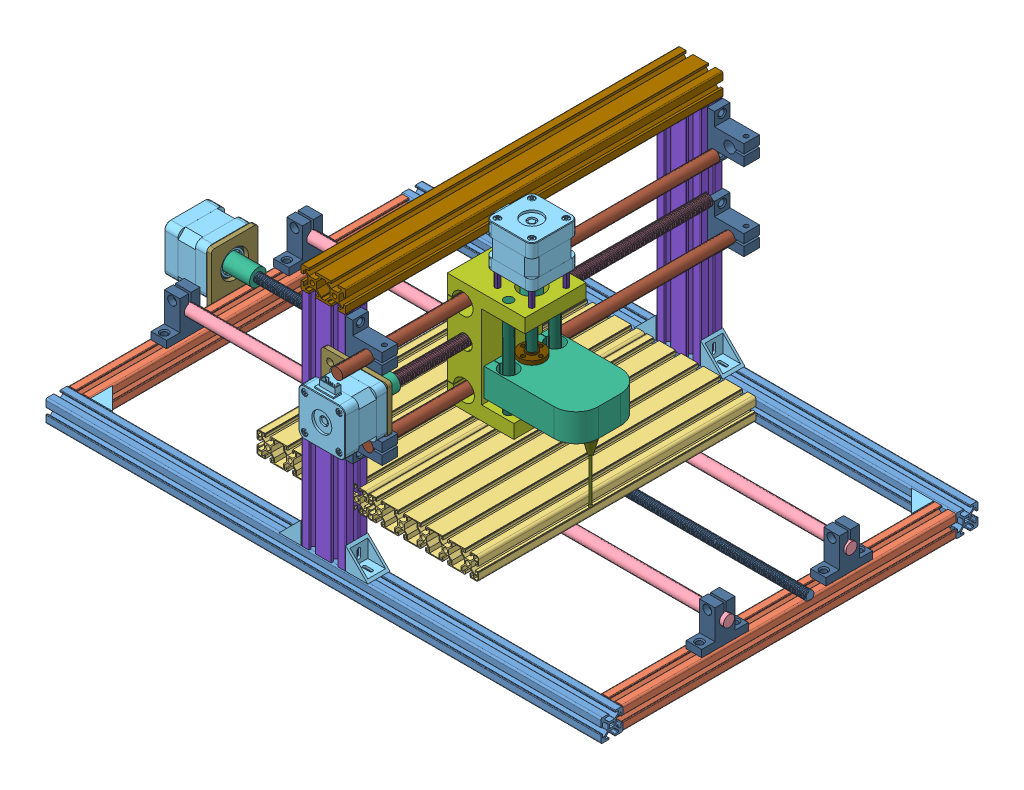
SolidWorks assembly CMM_v2, configuration Default. Lengths in mm.
Overall size (560.56 265.37 382.4).
67 component instances, 25 part files, 156 mates.
Components (placement in the parent):
- ALU 500-2: ALU 500 [Default] at (-29.4139 -47.6481 461.8459) x (0 0 -1) z (1 0 0) size (20 20 500)
- ALU 500-3: ALU 500 [Default] at (-29.4139 -47.6481 141.8459) x (0 0 -1) z (1 0 0) size (20 20 500)
- ALU 300-2: ALU 300 [Default] at (-19.4139 -47.6481 151.8459) size (20 20 300)
- ALU 300-3: ALU 300 [Default] at (460.5861 -47.6481 151.8459) size (20 20 300)
- ban_nhom-1: ban_nhom [Default] at (158.2326 11.3519 209.5255) size (100 20 250)
- ban_nhom-2: ban_nhom [Default] at (258.2326 11.3519 209.5255) size (100 20 250)
- truc_10-1: truc_10 [Default] at (-29.4139 -17.6481 245.8459) x (0 -1 0) z (0 0 1) size (10 500 10)
- truc_10-2: truc_10 [Default] at (-27.7739 -17.6481 357.8459) x (0 -1 0) z (0 0 1) size (10 500 10)
- nema 17-4: nema 17 [Default] at (-33.4139 -17.6481 301.8459) x (0 0 -1) z (1 0 0) size (42 48.2 62.55)
- khop_noi_truc-1: khop_noi_truc [Default] at (-8.4139 -17.6481 301.8459) x (0 0.838957 0.544198) z (0 -0.544198 0.838957) size (15 25 15)
- lmu10-1: lmu10 [Default] at (277.237 -17.6481 245.8459) x (0 1 0) z (0 0 1) size (16 32 16)
- lmu10-2: lmu10 [Default] at (307.4891 -17.6481 357.8459) x (0 1 0) z (0 0 1) size (16 32 16)
- Aluminum Profile 2040-1: Aluminum Profile 2040 [Default] at (220.5861 162.3519 141.8459) x (0 0 -1) z (0 1 0) size (20 40 200)
- Aluminum Profile 2040-2: Aluminum Profile 2040 [Default] at (220.5861 162.3519 461.8459) x (0 0 -1) z (0 1 0) size (20 40 200)
- Aluminum Profile 2040 300mm-1: Aluminum Profile 2040 300mm [Default] at (220.5861 172.3519 471.8459) x (0 -1 0) z (0 0 1) size (20 40 340)
- SK10-1: SK10 [Default] at (240.5861 49.3219 471.8459) x (0 0 -1) z (0 -1 0) size (14 33 42)
- SK10-2: SK10 [Default] at (240.5861 49.3219 145.8459) x (0 0 -1) z (0 -1 0) size (14 33 42)
- SK10-3: SK10 [Default] at (240.5861 119.5072 145.8459) x (0 0 -1) z (0 -1 0) size (14 33 42)
- SK10-5: SK10 [Default] at (240.5861 119.5072 471.8459) x (0 0 -1) z (0 -1 0) size (14 33 42)
- truc_10_340mm-1: truc_10_340mm [Default] at (260.5861 140.5072 499.541) x (0.996943 -0.078134 0) z (0.078134 0.996943 0) size (10 340 10)
- truc_10_340mm-2: truc_10_340mm [Default] at (260.5861 70.3219 471.8459) x (0.996923 -0.07839 0) z (0.07839 0.996923 0) size (10 340 10)
- ga_dong_co-1: ga_dong_co [Default] at (252.5861 110.2153 475.8459) x (1 0 0) z (0 1 0) size (60 4 42)
- nema 17-5: nema 17 [Default] at (261.5861 110.2153 475.8459) x (1 0 0) z (0 0 -1) size (42 48.2 62.55)
- khop_noi_truc-2: khop_noi_truc [Default] at (261.5861 110.2153 450.8459) x (0.544198 0.838957 0) z (0.838957 -0.544198 0) size (15 25 15)
- Vitme M10 step2mm profile by Taitran Technic-5: Vitme M10 step2mm profile by Taitran Technic [Default] at (261.5861 110.2153 165.8459) x (-0.97024 -0.242147 0) z (-0.242147 0.97024 0) size (10.57 95.57 10.57)
- Vitme M10 step2mm profile by Taitran Technic-6: Vitme M10 step2mm profile by Taitran Technic [Default] at (261.5861 110.2153 260.8459) x (-0.97024 -0.242147 0) z (-0.242147 0.97024 0) size (10.57 95.57 10.57)
- Vitme M10 step2mm profile by Taitran Technic-7: Vitme M10 step2mm profile by Taitran Technic [Default] at (261.5861 110.2153 450.8459) x (0.146687 -0.989183 0) z (0.989183 0.146687 0) size (10.57 95.57 10.57)
- Leadscrew nut M10 step2mm by Taitran Technic-2: Leadscrew nut M10 step2mm by Taitran Technic [Default] at (261.5861 110.2153 330.15) x (-0.214668 -0.976687 0) z (0.976687 -0.214668 0) size (32 19 32)
- nema 17-6: nema 17 [Default] at (294.2592 169.3219 357.65) x (0 0 -1) z (0 -1 0) size (42 48.2 62.55)
- truc_8-1: truc_8 [Default] at (294.2592 54.3219 336.75) size (8 100 8)
- truc_8-2: truc_8 [Default] at (294.2592 54.3219 378.55) size (8 100 8)
- Stylus with thread, M3 XXT Ø 1,50 626113-0151-030-1: Stylus with thread, M3 XXT Ø 1,50 626113-0151-030 [Default] at (354.4778 73.7923 364.8995) x (1 0 0) z (0 -1 0) size (10 10 66)
- khop_noi_truc-3: khop_noi_truc [Default] at (294.2592 144.3219 357.65) x (0.28811 0 -0.957597) z (0.957597 0 0.28811) size (15 25 15)
- coc_dong-1: coc_dong [Default] at (309.7592 154.3219 373.15) size (4.52 23 4.69)
- coc_dong-2: coc_dong [Default] at (309.7592 154.3219 342.15) size (4.52 23 4.69)
- coc_dong-3: coc_dong [Default] at (278.7592 152.2216 373.15) size (4.52 23 4.69)
- coc_dong-4: coc_dong [Default] at (278.7592 154.3219 342.15) size (4.52 23 4.69)
- truc_8-3: truc_8 [Default] at (294.2592 49.7177 357.65) x (0.933443 0 -0.358725) z (0.358725 0 0.933443) size (8 100 8)
- leadscrew m8-1: leadscrew m8 [Default] at (294.2592 100.6553 357.65) size (22 15.03 22)
- ga_dong_co-2: ga_dong_co [Default] at (-33.4139 -26.6481 301.8459) x (0 1 0) z (0 0 -1) size (60 4 42)
- SK10-6: SK10 [Default] at (454.5861 -37.6481 378.8459) size (14 33 42)
- SK10-7: SK10 [Default] at (454.5861 -37.6481 266.8459) size (14 33 42)
- SK10-8: SK10 [Default] at (-29.4139 -37.6481 266.8459) size (14 33 42)
- SK10-9: SK10 [Default] at (-27.7739 -37.6481 378.8459) size (14 33 42)
- Vitme M8 step2mm profile by Taitran Technic-1: Vitme M8 step2mm profile by Taitran Technic [Default] at (-9.2639 -17.6481 301.8459) x (0 -1 0) z (0 0 1) size (8.43 83.01 8.22)
- Vitme M8 step2mm profile by Taitran Technic-2: Vitme M8 step2mm profile by Taitran Technic [Default] at (156.7361 -17.6481 301.8459) x (0 -1 0) z (0 0 1) size (8.43 83.01 8.22)
- Vitme M8 step2mm profile by Taitran Technic-3: Vitme M8 step2mm profile by Taitran Technic [Default] at (239.7361 -17.6481 301.8459) x (0 -1 0) z (0 0 1) size (8.43 83.01 8.22)
- Vitme M8 step2mm profile by Taitran Technic-4: Vitme M8 step2mm profile by Taitran Technic [Default] at (73.7361 -17.6481 301.8459) x (0 -1 0) z (0 0 1) size (8.43 83.01 8.22)
- Vitme M8 step2mm profile by Taitran Technic-5: Vitme M8 step2mm profile by Taitran Technic [Default] at (322.7361 -17.6481 301.8459) x (0 -1 0) z (0 0 1) size (8.43 83.01 8.22)
- Vitme M8 step2mm profile by Taitran Technic-6: Vitme M8 step2mm profile by Taitran Technic [Default] at (405.7361 -17.6481 301.8459) x (0 -1 0) z (0 0 1) size (8.43 83.01 8.22)
- goi_do_dai - Copy-1: goi_do_dai - Copy [Default] at (158.6614 -13.6481 301.8459) x (0 0 1) z (0 1 0) size (57.67 30 30)
- goi_do_dai-1: goi_do_dai [Default] at (247.237 -13.6481 245.8459) x (0 0 1) z (0 1 0) size (57.67 30 31)
- goi_do_dai-2: goi_do_dai [Default] at (277.4891 -13.6481 357.8459) x (0 0 1) z (0 1 0) size (57.67 30 31)
- goi_do_dai-3: goi_do_dai [Default] at (137.237 -13.6481 245.8459) x (0 0 1) z (0 1 0) size (57.67 30 31)
- goi_do_dai-4: goi_do_dai [Default] at (167.4891 -13.6481 357.8459) x (0 0 1) z (0 1 0) size (57.67 30 31)
- Leadscrew nut M8 step2mm by Taitran Technic1-1: Leadscrew nut M8 step2mm by Taitran Technic1 [Default] at (188.6614 -17.6481 301.8459) x (0 1 0) z (0 0 -1) size (22 15.03 22)
- profile angle 20x20-1: profile angle 20x20 [Default] at (250.5861 -27.6481 451.8459) size (20 20 20)
- profile angle 20x20-2: profile angle 20x20 [Default] at (440.5861 -37.6481 161.8459) x (0 0 1) z (0 -1 0) size (20 20 20)
- profile angle 20x20-3: profile angle 20x20 [Default] at (0.5861 -57.6481 441.8459) x (1 0 0) z (0 1 0) size (20 20 20)
- profile angle 20x20-4: profile angle 20x20 [Default] at (0.5861 -57.6481 161.8459) x (0 0 1) z (0 1 0) size (20 20 20)
- profile angle 20x20-6: profile angle 20x20 [Default] at (190.5861 -27.6481 471.8459) x (-1 0 0) z (0 0 -1) size (20 20 20)
- profile angle 20x20-7: profile angle 20x20 [Default] at (190.5861 -27.6481 131.8459) x (0 1 0) z (0 0 1) size (20 20 20)
- profile angle 20x20-8: profile angle 20x20 [Default] at (250.5861 -27.6481 131.8459) size (20 20 20)
- profile angle 20x20-9: profile angle 20x20 [Default] at (200.5861 152.3519 161.8459) x (0 0 1) z (1 0 0) size (20 20 20)
- profile angle 20x20-10: profile angle 20x20 [Default] at (200.5861 152.3519 441.8459) x (0 -1 0) z (1 0 0) size (20 20 20)
- DC_motor_holder_1-1: DC_motor_holder_1 [Default] at (324.2241 75.6553 357.65) x (0 0 1) z (-1 0 0) size (60 25 83)
- ga_1-1: ga_1 [Default] at (280.5861 104.3219 385.15) x (0 1 0) z (-1 0 0) size (100 55 70)
Mates (geometry in assembly coordinates):
- Coincident23: coincident anti-aligned: plane of ALU 500-3 through (470.5861 -47.6481 151.8459) normal (0 0 1); plane of ALU 300-2 through (-19.4139 -47.6481 151.8459) normal (0 0 -1)
- Coincident78: coincident anti-aligned: plane of ban_nhom-1 through (248.2326 13.9019 209.5255) normal (1 0 0); plane of ban_nhom-2 through (248.2326 8.8019 209.5255) normal (-1 0 0)
- Coincident79: coincident aligned: plane of ban_nhom-1 through (245.9826 21.3519 209.5255) normal (0 1 0); plane of ban_nhom-2 through (255.6826 21.3519 209.5255) normal (0 1 0)
- Coincident80: coincident aligned: plane of ban_nhom-1 through (158.2326 11.3519 459.5255) normal (0 0 1); plane of ban_nhom-2 through (258.2326 11.3519 459.5255) normal (0 0 1)
- Concentric7: concentric anti-aligned: cylinder of nema 17-4 through (-9.2639 -17.6481 301.8459) axis (-1 0 0) radius 2.5; cylinder of khop_noi_truc-1 through (-33.4139 -17.6481 301.8459) axis (1 0 0) radius 4
- Coincident117: coincident anti-aligned: plane of nema 17-4 through (-33.4139 -17.6481 301.8459) normal (1 0 0); plane of khop_noi_truc-1 through (-33.4139 -17.6481 301.8459) normal (-1 0 0)
- Concentric16: concentric anti-aligned: cylinder of truc_10-1 through (470.5861 -17.6481 245.8459) axis (-1 0 0) radius 5; cylinder of lmu10-1 through (245.237 -17.6481 245.8459) axis (1 0 0) radius 8
- Concentric17: concentric anti-aligned: cylinder of truc_10-2 through (472.2261 -17.6481 357.8459) axis (-1 0 0) radius 5; cylinder of lmu10-2 through (275.4891 -17.6481 357.8459) axis (1 0 0) radius 8
- Coincident140: coincident aligned: plane of ban_nhom-1 through (198.2326 11.3519 209.5255) normal (0 0 -1); plane of ban_nhom-2 through (298.2326 11.3519 209.5255) normal (0 0 -1)
- Coincident142: coincident anti-aligned: plane of ALU 500-3 through (470.5861 -37.6481 141.8459) normal (0 1 0); plane of Aluminum Profile 2040-1 through (239.5861 -37.6481 132.8459) normal (0 -1 0)
- Coincident143: coincident aligned: plane of ALU 500-3 through (470.5861 -47.6481 131.8459) normal (0 0 -1); plane of Aluminum Profile 2040-1 through (207.5861 -37.6481 131.8459) normal (0 0 -1)
- Distance9: distance = 230 mm aligned: plane of Aluminum Profile 2040-1 through (200.5861 -37.6481 132.8459) normal (-1 0 0); plane of ALU 500-3 through (-29.4139 -47.6481 141.8459) normal (-1 0 0)
- Coincident145: coincident anti-aligned: plane of ALU 500-2 through (470.5861 -37.6481 461.8459) normal (0 1 0); plane of Aluminum Profile 2040-2 through (239.5861 -37.6481 452.8459) normal (0 -1 0)
- Coincident146: coincident aligned: plane of ALU 500-2 through (470.5861 -47.6481 471.8459) normal (0 0 1); plane of Aluminum Profile 2040-2 through (213.5861 -37.6481 471.8459) normal (0 0 1)
- Coincident147: coincident anti-aligned: plane of ALU 500-2 through (470.5861 -47.6481 451.8459) normal (0 0 -1); plane of ALU 300-2 through (-19.4139 -47.6481 451.8459) normal (0 0 1)
- Coincident148: coincident: line of ALU 500-2; line of ALU 300-2 through (-29.4139 -44.5162 451.8459) axis (0 0 -1)
- Coincident149: coincident aligned: plane of Aluminum Profile 2040-1 through (200.5861 -37.6481 144.8459) normal (-1 0 0); plane of Aluminum Profile 2040-2 through (200.5861 -37.6481 452.8459) normal (-1 0 0)
- Coincident150: coincident anti-aligned: plane of Aluminum Profile 2040-2 through (239.5861 162.3519 452.8459) normal (0 1 0); plane of Aluminum Profile 2040 300mm-1 through (213.5861 162.3519 131.8459) normal (0 -1 0)
- Coincident151: coincident aligned: plane of Aluminum Profile 2040-2 through (240.5861 -37.6481 458.8459) normal (1 0 0); plane of Aluminum Profile 2040 300mm-1 through (240.5861 175.3519 131.8459) normal (1 0 0)
- Coincident152: coincident aligned: plane of Aluminum Profile 2040-2 through (213.5861 -37.6481 471.8459) normal (0 0 1); plane of Aluminum Profile 2040 300mm-1 through (201.5861 163.3519 471.8459) normal (0 0 1)
- Coincident153: coincident anti-aligned: plane of Aluminum Profile 2040-2 through (240.5861 -37.6481 458.8459) normal (1 0 0); plane of SK10-1 through (240.5861 49.3219 471.8459) normal (-1 0 0)
- Coincident154: coincident aligned: plane of Aluminum Profile 2040-2 through (233.5861 -37.6481 471.8459) normal (0 0 1); plane of SK10-1 through (257.0861 70.3219 471.8459) normal (0 0 1)
- Coincident155: coincident anti-aligned: plane of Aluminum Profile 2040-2 through (240.5861 -37.6481 458.8459) normal (1 0 0); plane of SK10-5 through (240.5861 119.5072 471.8459) normal (-1 0 0)
- Coincident156: coincident aligned: plane of Aluminum Profile 2040-2 through (233.5861 -37.6481 471.8459) normal (0 0 1); plane of SK10-5 through (257.0861 140.5072 471.8459) normal (0 0 1)
- Coincident157: coincident anti-aligned: plane of Aluminum Profile 2040-1 through (240.5861 -37.6481 138.8459) normal (1 0 0); plane of SK10-2 through (240.5861 49.3219 145.8459) normal (-1 0 0)
- Coincident158: coincident aligned: plane of Aluminum Profile 2040-1 through (239.5861 -37.6481 131.8459) normal (0 0 -1); plane of SK10-2 through (257.0861 70.3219 131.8459) normal (0 0 -1)
- Coincident159: coincident aligned: plane of Aluminum Profile 2040-1 through (239.5861 -37.6481 131.8459) normal (0 0 -1); plane of SK10-3 through (257.0861 140.5072 131.8459) normal (0 0 -1)
- Coincident160: coincident anti-aligned: plane of Aluminum Profile 2040-1 through (240.5861 -37.6481 138.8459) normal (1 0 0); plane of SK10-3 through (240.5861 119.5072 145.8459) normal (-1 0 0)
- Concentric19: concentric aligned: cylinder of SK10-3 through (260.5861 140.5072 145.8459) axis (0 0 -1) radius 5; cylinder of SK10-5 through (260.5861 140.5072 471.8459) axis (0 0 -1) radius 5
- Concentric20: concentric aligned: cylinder of SK10-1 through (260.5861 70.3219 471.8459) axis (0 0 -1) radius 5; cylinder of SK10-2 through (260.5861 70.3219 145.8459) axis (0 0 -1) radius 5
- Concentric22: concentric anti-aligned: cylinder of SK10-5 through (260.5861 140.5072 471.8459) axis (0 0 -1) radius 5; cylinder of truc_10_340mm-1 through (260.5861 140.5072 159.541) axis (0 0 1) radius 5
- Concentric23: concentric anti-aligned: cylinder of SK10-1 through (260.5861 70.3219 471.8459) axis (0 0 -1) radius 5; cylinder of truc_10_340mm-2 through (260.5861 70.3219 131.8459) axis (0 0 1) radius 5
- Coincident162: coincident: point of SK10-1; plane of truc_10_340mm-2 through (260.5861 70.3219 471.8459) normal (0 0 1)
- Coincident163: coincident anti-aligned: plane of Aluminum Profile 2040-2 through (213.5861 -37.6481 471.8459) normal (0 0 1); plane of ga_dong_co-1 through (252.5861 110.2153 471.8459) normal (0 0 -1)
- Distance11: distance = 18 mm anti-aligned: plane of Aluminum Profile 2040-2 through (240.5861 -37.6481 470.8459) normal (1 0 0); plane of ga_dong_co-1 through (222.5861 89.2153 471.8459) normal (-1 0 0)
- Concentric24: concentric aligned: cylinder of ga_dong_co-1 through (261.5861 110.2153 471.8459) axis (0 0 1) radius 12.5; cylinder of nema 17-5 through (261.5861 110.2153 451.6959) axis (0 0 1) radius 2.5
- Coincident167: coincident anti-aligned: plane of ga_dong_co-1 through (252.5861 110.2153 475.8459) normal (0 0 1); plane of nema 17-5 through (261.5861 110.2153 475.8459) normal (0 0 -1)
- Coincident168: coincident aligned: plane of ga_dong_co-1 through (222.5861 131.2153 471.8459) normal (0 1 0); plane of nema 17-5 through (261.5861 131.2153 514.2459) normal (0 1 0)
- Concentric25: concentric anti-aligned: cylinder of nema 17-5 through (261.5861 110.2153 451.6959) axis (0 0 1) radius 2.5; cylinder of khop_noi_truc-2 through (261.5861 110.2153 475.8459) axis (0 0 -1) radius 4
- Coincident169: coincident anti-aligned: plane of nema 17-5 through (261.5861 110.2153 475.8459) normal (0 0 -1); plane of khop_noi_truc-2 through (261.5861 110.2153 475.8459) normal (0 0 1)
- Coincident170: coincident anti-aligned: plane of Vitme M10 step2mm profile by Taitran Technic-5 through (261.5861 110.2153 260.8459) normal (0 0 1); plane of Vitme M10 step2mm profile by Taitran Technic-6 through (261.5861 110.2153 260.8459) normal (0 0 -1)
- Concentric26: concentric aligned: cylinder of Vitme M10 step2mm profile by Taitran Technic-5 through (261.5861 110.2153 265.8459) axis (0 0 -1) radius 4; cylinder of Vitme M10 step2mm profile by Taitran Technic-6 through (261.5861 110.2153 360.8459) axis (0 0 -1) radius 4
- Coincident171: coincident anti-aligned: plane of Vitme M10 step2mm profile by Taitran Technic-6 through (261.5861 110.2153 355.8459) normal (0 0 1); plane of Vitme M10 step2mm profile by Taitran Technic-7 through (261.5861 110.2153 355.8459) normal (0 0 -1)
- Concentric27: concentric anti-aligned: cylinder of Vitme M10 step2mm profile by Taitran Technic-6 through (261.5861 110.2153 360.8459) axis (0 0 -1) radius 4; cylinder of Vitme M10 step2mm profile by Taitran Technic-7 through (261.5861 110.2153 350.8459) axis (0 0 1) radius 4
- Concentric28: concentric anti-aligned: cylinder of khop_noi_truc-2 through (261.5861 110.2153 475.8459) axis (0 0 -1) radius 7.5; cylinder of Vitme M10 step2mm profile by Taitran Technic-7 through (261.5861 110.2153 350.8459) axis (0 0 1) radius 4
- Coincident172: coincident anti-aligned: plane of khop_noi_truc-2 through (261.5861 110.2153 450.8459) normal (0 0 -1); plane of Vitme M10 step2mm profile by Taitran Technic-7 through (261.5861 110.2153 450.8459) normal (0 0 1)
- Concentric29: concentric anti-aligned: cylinder of khop_noi_truc-2 through (261.5861 110.2153 475.8459) axis (0 0 -1) radius 7.5; cylinder of Leadscrew nut M10 step2mm by Taitran Technic-2 through (261.5861 110.2153 330.15) axis (0 0 1) radius 8
- Coincident178: coincident aligned: plane of ALU 500-2 through (470.5861 -47.6481 461.8459) normal (1 0 0); plane of ALU 300-3 through (470.5861 -47.6481 451.8459) normal (1 0 0)
- Concentric49: concentric anti-aligned: cylinder of nema 17-6 through (294.2592 145.1719 357.65) axis (0 1 0) radius 2.5; cylinder of khop_noi_truc-3 through (294.2592 169.3219 357.65) axis (0 -1 0) radius 7.5
- Coincident208: coincident anti-aligned: plane of nema 17-6 through (294.2592 169.3219 357.65) normal (0 -1 0); plane of khop_noi_truc-3 through (294.2592 169.3219 357.65) normal (0 1 0)
- Coincident216: coincident anti-aligned: plane of nema 17-6 through (294.2592 169.3219 357.65) normal (0 -1 0); plane of coc_dong-2 through (309.7592 169.3219 342.15) normal (0 1 0)
- Concentric54: concentric aligned: cylinder of khop_noi_truc-3 through (294.2592 169.3219 357.65) axis (0 -1 0) radius 4; cylinder of truc_8-3 through (294.2592 149.7177 357.65) axis (0 -1 0) radius 4
- Concentric55: concentric anti-aligned: cylinder of truc_8-3 through (294.2592 149.7177 357.65) axis (0 -1 0) radius 4; cylinder of leadscrew m8-1 through (294.2592 90.6553 357.65) axis (0 1 0) radius 5
- Concentric56: concentric anti-aligned: cylinder of khop_noi_truc-1 through (-33.4139 -17.6481 301.8459) axis (1 0 0) radius 7.5; cylinder of ga_dong_co-2 through (-29.4139 -17.6481 301.8459) axis (-1 0 0) radius 12.5
- Coincident220: coincident anti-aligned: plane of nema 17-4 through (-33.4139 -17.6481 301.8459) normal (1 0 0); plane of ga_dong_co-2 through (-33.4139 -26.6481 301.8459) normal (-1 0 0)
- Coincident240: coincident: plane of ALU 500-2 through (470.5861 -37.6481 461.8459) normal (0 1 0); line of ALU 300-2 through (-10.9139 -37.6481 451.8459) axis (0 0 -1)
- Coincident241: coincident aligned: plane of ALU 500-2 through (-29.4139 -47.6481 461.8459) normal (-1 0 0); plane of ALU 300-2 through (-29.4139 -47.6481 451.8459) normal (-1 0 0)
- Coincident243: coincident: line of ALU 500-2 through (470.5861 -37.6481 453.3459) axis (-1 0 0); plane of ALU 300-3 through (460.5861 -37.6481 451.8459) normal (0 1 0)
- Coincident244: coincident anti-aligned: circle of ALU 500-2; circle of ALU 300-3
- Coincident245: coincident aligned: plane of ALU 500-3 through (470.5861 -47.6481 141.8459) normal (1 0 0); plane of ALU 300-3 through (470.5861 -47.6481 451.8459) normal (1 0 0)
- Coincident246: coincident anti-aligned: plane of ALU 300-3 through (460.5861 -37.6481 451.8459) normal (0 1 0); plane of SK10-6 through (454.5861 -37.6481 378.8459) normal (0 -1 0)
- Distance26: distance = 2 mm aligned: plane of SK10-6 through (468.5861 -21.1481 357.8459) normal (1 0 0); plane of ALU 300-3 through (470.5861 -47.6481 451.8459) normal (1 0 0)
- Coincident248: coincident anti-aligned: plane of ALU 300-3 through (460.5861 -37.6481 451.8459) normal (0 1 0); plane of SK10-7 through (454.5861 -37.6481 266.8459) normal (0 -1 0)
- Distance27: distance = 2 mm aligned: plane of ALU 300-3 through (470.5861 -47.6481 451.8459) normal (1 0 0); plane of SK10-7 through (468.5861 -21.1481 245.8459) normal (1 0 0)
- Coincident250: coincident aligned: plane of ALU 300-2 through (-29.4139 -47.6481 451.8459) normal (-1 0 0); plane of SK10-8 through (-29.4139 -21.1481 245.8459) normal (-1 0 0)
- Coincident251: coincident anti-aligned: plane of ALU 300-2 through (-19.4139 -37.6481 451.8459) normal (0 1 0); plane of SK10-8 through (-29.4139 -37.6481 266.8459) normal (0 -1 0)
- Concentric57: concentric aligned: cylinder of SK10-7 through (454.5861 -17.6481 245.8459) axis (1 0 0) radius 5; cylinder of SK10-8 through (-29.4139 -17.6481 245.8459) axis (1 0 0) radius 5
- Coincident252: coincident: line of ALU 300-2 through (-27.7739 -42.155 451.8459) axis (0 0 -1); plane of SK10-9 through (-27.7739 -21.1481 357.8459) normal (-1 0 0)
- Coincident253: coincident anti-aligned: plane of ALU 300-2 through (-19.4139 -37.6481 451.8459) normal (0 1 0); plane of SK10-9 through (-27.7739 -37.6481 378.8459) normal (0 -1 0)
- Concentric58: concentric anti-aligned: cylinder of truc_10-1 through (470.5861 -17.6481 245.8459) axis (-1 0 0) radius 5; cylinder of SK10-8 through (-29.4139 -17.6481 245.8459) axis (1 0 0) radius 5
- Coincident254: coincident aligned: plane of truc_10-1 through (-29.4139 -17.6481 245.8459) normal (-1 0 0); plane of SK10-8 through (-29.4139 -21.1481 245.8459) normal (-1 0 0)
- Concentric59: concentric anti-aligned: cylinder of truc_10-2 through (472.2261 -17.6481 357.8459) axis (-1 0 0) radius 5; cylinder of SK10-9 through (-27.7739 -17.6481 357.8459) axis (1 0 0) radius 5
- Coincident255: coincident aligned: plane of truc_10-2 through (-27.7739 -17.6481 357.8459) normal (-1 0 0); plane of SK10-9 through (-27.7739 -21.1481 357.8459) normal (-1 0 0)
- Concentric60: concentric anti-aligned: cylinder of truc_10-2 through (472.2261 -17.6481 357.8459) axis (-1 0 0) radius 5; cylinder of SK10-6 through (454.5861 -17.6481 357.8459) axis (1 0 0) radius 5
- Distance28: distance = 70 mm anti-aligned: plane of SK10-8 through (-29.4139 -31.1481 266.8459) normal (0 0 1); plane of SK10-9 through (-27.7739 -37.6481 336.8459) normal (0 0 -1)
- Coincident258: coincident: plane of ALU 500-3 through (470.5861 -37.6481 141.8459) normal (0 1 0); line of ALU 300-2 through (-27.9139 -37.6481 451.8459) axis (0 0 -1)
- Coincident259: coincident aligned: plane of ga_dong_co-2 through (-33.4139 -26.6481 301.8459) normal (0 0 -1)
- Coincident260: coincident aligned: plane of ga_dong_co-2 through (-33.4139 -26.6481 301.8459) normal (0 0 -1)
- Coincident261: coincident anti-aligned: plane of Vitme M8 step2mm profile by Taitran Technic-2 through (239.7361 -17.6481 301.8459) normal (1 0 0); plane of Vitme M8 step2mm profile by Taitran Technic-3 through (239.7361 -17.6481 301.8459) normal (-1 0 0)
- Concentric61: concentric aligned: cylinder of Vitme M8 step2mm profile by Taitran Technic-2 through (256.7361 -17.6481 301.8459) axis (-1 0 0) radius 3; cylinder of Vitme M8 step2mm profile by Taitran Technic-3 through (339.7361 -17.6481 301.8459) axis (-1 0 0) radius 3
- Coincident262: coincident anti-aligned: plane of Vitme M8 step2mm profile by Taitran Technic-2 through (156.7361 -17.6481 301.8459) normal (-1 0 0); plane of Vitme M8 step2mm profile by Taitran Technic-4 through (156.7361 -17.6481 301.8459) normal (1 0 0)
- Concentric62: concentric aligned: cylinder of Vitme M8 step2mm profile by Taitran Technic-2 through (256.7361 -17.6481 301.8459) axis (-1 0 0) radius 3; cylinder of Vitme M8 step2mm profile by Taitran Technic-4 through (173.7361 -17.6481 301.8459) axis (-1 0 0) radius 3
- Coincident263: coincident anti-aligned: plane of Vitme M8 step2mm profile by Taitran Technic-1 through (73.7361 -17.6481 301.8459) normal (1 0 0); plane of Vitme M8 step2mm profile by Taitran Technic-4 through (73.7361 -17.6481 301.8459) normal (-1 0 0)
- Concentric63: concentric aligned: cylinder of Vitme M8 step2mm profile by Taitran Technic-1 through (90.7361 -17.6481 301.8459) axis (-1 0 0) radius 3; cylinder of Vitme M8 step2mm profile by Taitran Technic-4 through (173.7361 -17.6481 301.8459) axis (-1 0 0) radius 3
- Concentric64: concentric anti-aligned: cylinder of khop_noi_truc-1 through (-33.4139 -17.6481 301.8459) axis (1 0 0) radius 7.5; cylinder of Vitme M8 step2mm profile by Taitran Technic-1 through (90.7361 -17.6481 301.8459) axis (-1 0 0) radius 3
- Coincident264: coincident anti-aligned: plane of nema 17-4 through (-9.2639 -17.6481 301.8459) normal (1 0 0); plane of Vitme M8 step2mm profile by Taitran Technic-1 through (-9.2639 -17.6481 301.8459) normal (-1 0 0)
- Coincident265: coincident anti-aligned: plane of Vitme M8 step2mm profile by Taitran Technic-3 through (322.7361 -17.6481 301.8459) normal (1 0 0); plane of Vitme M8 step2mm profile by Taitran Technic-5 through (322.7361 -17.6481 301.8459) normal (-1 0 0)
- Concentric65: concentric aligned: cylinder of Vitme M8 step2mm profile by Taitran Technic-3 through (339.7361 -17.6481 301.8459) axis (-1 0 0) radius 3; cylinder of Vitme M8 step2mm profile by Taitran Technic-5 through (422.7361 -17.6481 301.8459) axis (-1 0 0) radius 3
- Coincident270: coincident anti-aligned: plane of Vitme M8 step2mm profile by Taitran Technic-5 through (405.7361 -17.6481 301.8459) normal (1 0 0); plane of Vitme M8 step2mm profile by Taitran Technic-6 through (405.7361 -17.6481 301.8459) normal (-1 0 0)
- Concentric69: concentric aligned: cylinder of Vitme M8 step2mm profile by Taitran Technic-5 through (422.7361 -17.6481 301.8459) axis (-1 0 0) radius 3; cylinder of Vitme M8 step2mm profile by Taitran Technic-6 through (505.7361 -17.6481 301.8459) axis (-1 0 0) radius 3
- Coincident271: coincident anti-aligned: plane of ban_nhom-1 through (200.7826 1.3519 209.5255) normal (0 -1 0); plane of goi_do_dai - Copy-1 through (188.6614 1.3519 273.012) normal (0 1 0)
- Parallel28: parallel anti-aligned: plane of ALU 500-3 through (470.5861 -37.6481 141.8459) normal (0 1 0); plane of goi_do_dai - Copy-1 through (158.6614 -1.6481 301.8459) normal (0 -1 0)
- Parallel29: parallel anti-aligned: plane of ban_nhom-2 through (280.7826 1.3519 209.5255) normal (0 -1 0); plane of goi_do_dai-1 through (277.237 1.3519 217.012) normal (0 1 0)
- Coincident274: coincident aligned: plane of lmu10-1 through (277.237 -17.6481 245.8459) normal (1 0 0); plane of goi_do_dai-1 through (277.237 -13.6481 245.8459) normal (1 0 0)
- Coincident275: coincident aligned: plane of lmu10-2 through (307.4891 -17.6481 357.8459) normal (1 0 0); plane of goi_do_dai-2 through (307.4891 -13.6481 357.8459) normal (1 0 0)
- Distance29: distance = 80 mm anti-aligned: plane of goi_do_dai-4 through (197.4891 -13.6481 357.8459) normal (1 0 0); plane of goi_do_dai-2 through (277.4891 -13.6481 357.8459) normal (-1 0 0)
- Distance30: distance = 80 mm anti-aligned: plane of goi_do_dai-3 through (167.237 -13.6481 245.8459) normal (1 0 0); plane of goi_do_dai-1 through (247.237 -13.6481 245.8459) normal (-1 0 0)
- Coincident278: coincident anti-aligned: plane of goi_do_dai - Copy-1 through (188.6614 -13.6481 301.8459) normal (1 0 0); plane of Leadscrew nut M8 step2mm by Taitran Technic1-1 through (188.6614 -17.6481 301.8459) normal (-1 0 0)
- Concentric76: concentric anti-aligned: cylinder of goi_do_dai - Copy-1 through (178.6614 -17.6481 293.8459) axis (1 0 0) radius 1; cylinder of Leadscrew nut M8 step2mm by Taitran Technic1-1 through (192.1614 -17.6481 293.8459) axis (-1 0 0) radius 1.75
- Coincident279: coincident anti-aligned: plane of Aluminum Profile 2040-2 through (240.5861 -37.6481 458.8459) normal (1 0 0); plane of profile angle 20x20-1 through (240.5861 -37.6481 471.8459) normal (-1 0 0)
- Coincident280: coincident aligned: plane of Aluminum Profile 2040-2 through (233.5861 -37.6481 471.8459) normal (0 0 1); plane of profile angle 20x20-1 through (250.5861 -27.6481 471.8459) normal (0 0 1)
- Coincident281: coincident anti-aligned: plane of ALU 500-2 through (470.5861 -37.6481 461.8459) normal (0 1 0); plane of profile angle 20x20-1 through (240.5861 -37.6481 471.8459) normal (0 -1 0)
- Coincident282: coincident anti-aligned: plane of Aluminum Profile 2040-2 through (200.5861 -37.6481 464.8459) normal (-1 0 0); plane of profile angle 20x20-6 through (200.5861 -37.6481 451.8459) normal (1 0 0)
- Coincident283: coincident anti-aligned: plane of ALU 500-2 through (470.5861 -37.6481 461.8459) normal (0 1 0); plane of profile angle 20x20-6 through (200.5861 -37.6481 451.8459) normal (0 -1 0)
- Coincident284: coincident aligned: plane of Aluminum Profile 2040-2 through (201.5861 -37.6481 471.8459) normal (0 0 1); plane of profile angle 20x20-6 through (190.5861 -27.6481 471.8459) normal (0 0 1)
- Coincident285: coincident anti-aligned: plane of ALU 300-2 through (-9.4139 -47.6481 451.8459) normal (1 0 0); plane of profile angle 20x20-3 through (-9.4139 -37.6481 451.8459) normal (-1 0 0)
- Coincident286: coincident anti-aligned: plane of ALU 500-2 through (470.5861 -47.6481 451.8459) normal (0 0 -1); plane of profile angle 20x20-3 through (-9.4139 -37.6481 451.8459) normal (0 0 1)
- Coincident287: coincident aligned: plane of ALU 500-2 through (470.5861 -37.6481 461.8459) normal (0 1 0); plane of profile angle 20x20-3 through (0.5861 -37.6481 441.8459) normal (0 1 0)
- Coincident288: coincident anti-aligned: plane of ALU 500-3 through (470.5861 -47.6481 151.8459) normal (0 0 1); plane of profile angle 20x20-4 through (-9.4139 -37.6481 151.8459) normal (0 0 -1)
- Coincident291: coincident anti-aligned: plane of ALU 300-2 through (-9.4139 -47.6481 451.8459) normal (1 0 0); plane of profile angle 20x20-4 through (-9.4139 -37.6481 151.8459) normal (-1 0 0)
- Coincident292: coincident: line of ALU 300-2 through (-16.282 -37.6481 451.8459) axis (0 0 -1); plane of profile angle 20x20-4 through (0.5861 -37.6481 161.8459) normal (0 1 0)
- Coincident296: coincident anti-aligned: plane of ALU 300-3 through (450.5861 -47.6481 451.8459) normal (-1 0 0); plane of profile angle 20x20-2 through (450.5861 -57.6481 151.8459) normal (1 0 0)
- Coincident297: coincident aligned: plane of ALU 300-3 through (460.5861 -37.6481 451.8459) normal (0 1 0); plane of profile angle 20x20-2 through (440.5861 -37.6481 161.8459) normal (0 1 0)
- Coincident298: coincident anti-aligned: plane of ALU 500-3 through (470.5861 -47.6481 151.8459) normal (0 0 1); plane of profile angle 20x20-2 through (450.5861 -57.6481 151.8459) normal (0 0 -1)
- Coincident299: coincident anti-aligned: plane of ALU 500-3 through (470.5861 -37.6481 141.8459) normal (0 1 0); plane of profile angle 20x20-7 through (200.5861 -37.6481 151.8459) normal (0 -1 0)
- Coincident300: coincident anti-aligned: plane of Aluminum Profile 2040-1 through (200.5861 -37.6481 132.8459) normal (-1 0 0); plane of profile angle 20x20-7 through (200.5861 -37.6481 151.8459) normal (1 0 0)
- Coincident301: coincident aligned: plane of ALU 500-3 through (470.5861 -47.6481 131.8459) normal (0 0 -1); plane of profile angle 20x20-7 through (190.5861 -27.6481 131.8459) normal (0 0 -1)
- Coincident302: coincident anti-aligned: plane of Aluminum Profile 2040-1 through (240.5861 -37.6481 138.8459) normal (1 0 0); plane of profile angle 20x20-8 through (240.5861 -37.6481 151.8459) normal (-1 0 0)
- Coincident303: coincident anti-aligned: plane of ALU 500-3 through (470.5861 -37.6481 141.8459) normal (0 1 0); plane of profile angle 20x20-8 through (240.5861 -37.6481 151.8459) normal (0 -1 0)
- Coincident304: coincident aligned: plane of Aluminum Profile 2040-1 through (239.5861 -37.6481 131.8459) normal (0 0 -1); plane of profile angle 20x20-8 through (250.5861 -27.6481 131.8459) normal (0 0 -1)
- Coincident306: coincident anti-aligned: plane of Aluminum Profile 2040 300mm-1 through (201.5861 162.3519 131.8459) normal (0 -1 0); plane of profile angle 20x20-10 through (220.5861 162.3519 451.8459) normal (0 1 0)
- Coincident307: coincident aligned: plane of Aluminum Profile 2040-2 through (200.5861 -37.6481 452.8459) normal (-1 0 0); plane of profile angle 20x20-10 through (200.5861 152.3519 441.8459) normal (-1 0 0)
- Coincident308: coincident anti-aligned: plane of Aluminum Profile 2040-2 through (207.5861 -37.6481 451.8459) normal (0 0 -1); plane of profile angle 20x20-10 through (220.5861 162.3519 451.8459) normal (0 0 1)
- Coincident309: coincident anti-aligned: plane of Aluminum Profile 2040 300mm-1 through (201.5861 162.3519 131.8459) normal (0 -1 0); plane of profile angle 20x20-9 through (220.5861 162.3519 151.8459) normal (0 1 0)
- Coincident310: coincident aligned: plane of Aluminum Profile 2040-1 through (200.5861 -37.6481 144.8459) normal (-1 0 0); plane of profile angle 20x20-9 through (200.5861 152.3519 161.8459) normal (-1 0 0)
- Coincident311: coincident anti-aligned: plane of Aluminum Profile 2040-1 through (201.5861 -37.6481 151.8459) normal (0 0 1); plane of profile angle 20x20-9 through (220.5861 162.3519 151.8459) normal (0 0 -1)
- Parallel30: parallel aligned: plane of Aluminum Profile 2040 300mm-1 through (227.5861 182.3519 131.8459) normal (0 1 0); plane of ga_1-1 through (280.5861 154.3219 330.15) normal (0 1 0)
- Parallel31: parallel anti-aligned: plane of Aluminum Profile 2040 300mm-1 through (240.5861 175.3519 131.8459) normal (1 0 0); plane of ga_1-1 through (245.5861 104.3219 330.15) normal (-1 0 0)
- Concentric79: concentric aligned: cylinder of coc_dong-1 through (309.7592 150.3219 373.15) axis (0 1 0) radius 1.5; cylinder of ga_1-1 through (309.7592 119.3219 373.15) axis (0 1 0) radius 1.25
- Coincident316: coincident anti-aligned: plane of coc_dong-1 through (309.7592 154.3219 373.15) normal (0 -1 0); plane of ga_1-1 through (280.5861 154.3219 330.15) normal (0 1 0)
- Concentric80: concentric anti-aligned: cylinder of khop_noi_truc-3 through (294.2592 169.3219 357.65) axis (0 -1 0) radius 7.5; cylinder of ga_1-1 through (294.2592 119.3219 357.65) axis (0 1 0) radius 11
- Coincident317: coincident anti-aligned: plane of nema 17-6 through (294.2592 169.3219 357.65) normal (0 -1 0); plane of coc_dong-1 through (309.7592 169.3219 373.15) normal (0 1 0)
- Concentric81: concentric aligned: cylinder of coc_dong-2 through (309.7592 150.3219 342.15) axis (0 1 0) radius 1.5; circle of ga_1-1
- Coincident318: coincident anti-aligned: plane of coc_dong-2 through (309.7592 154.3219 342.15) normal (0 -1 0); plane of ga_1-1 through (280.5861 154.3219 330.15) normal (0 1 0)
- Concentric82: concentric aligned: cylinder of coc_dong-3 through (278.7592 148.2216 373.15) axis (0 1 0) radius 1.5; cylinder of ga_1-1 through (278.7592 119.3219 373.15) axis (0 1 0) radius 1.25
- Concentric83: concentric aligned: cylinder of coc_dong-4 through (278.7592 150.3219 342.15) axis (0 1 0) radius 1.5; cylinder of ga_1-1 through (278.7592 119.3219 342.15) axis (0 1 0) radius 1.25
- Coincident319: coincident anti-aligned: plane of coc_dong-4 through (278.7592 154.3219 342.15) normal (0 -1 0); plane of ga_1-1 through (280.5861 154.3219 330.15) normal (0 1 0)
- Concentric84: concentric anti-aligned: cylinder of truc_8-2 through (294.2592 154.3219 378.55) axis (0 -1 0) radius 4; cylinder of ga_1-1 through (294.2592 54.3219 378.55) axis (0 1 0) radius 4
- Coincident320: coincident aligned: plane of truc_8-2 through (294.2592 154.3219 378.55) normal (0 1 0); plane of ga_1-1 through (280.5861 154.3219 330.15) normal (0 1 0)
- Concentric85: concentric anti-aligned: cylinder of truc_8-1 through (294.2592 154.3219 336.75) axis (0 -1 0) radius 4; cylinder of ga_1-1 through (294.2592 54.3219 336.75) axis (0 1 0) radius 4
- Coincident321: coincident aligned: plane of truc_8-1 through (294.2592 154.3219 336.75) normal (0 1 0); plane of ga_1-1 through (280.5861 154.3219 330.15) normal (0 1 0)
- Concentric86: concentric anti-aligned: cylinder of truc_8-2 through (294.2592 154.3219 378.55) axis (0 -1 0) radius 4; cylinder of DC_motor_holder_1-1 through (294.2592 65.6553 378.55) axis (0 1 0) radius 7.95
- Concentric87: concentric anti-aligned: cylinder of truc_8-1 through (294.2592 154.3219 336.75) axis (0 -1 0) radius 4; circle of DC_motor_holder_1-1
- Coincident322: coincident anti-aligned: plane of leadscrew m8-1 through (294.2592 100.6553 357.65) normal (0 -1 0); plane of DC_motor_holder_1-1 through (324.2241 100.6553 357.65) normal (0 1 0)
- Concentric88: concentric anti-aligned: cylinder of truc_10_340mm-2 through (260.5861 70.3219 131.8459) axis (0 0 1) radius 5; cylinder of ga_1-1 through (260.5861 70.3219 385.15) axis (0 0 -1) radius 9.45
- Parallel32: parallel anti-aligned: cylinder of truc_10_340mm-1 through (260.5861 140.5072 159.541) axis (0 0 1) radius 5; cylinder of ga_1-1 through (259.3361 137.3219 385.15) axis (0 0 -1) radius 9.45
- Coincident323: coincident anti-aligned: plane of Leadscrew nut M10 step2mm by Taitran Technic-2 through (260.5127 105.3319 330.15) normal (0 0 1); plane of ga_1-1 through (280.5861 104.3219 330.15) normal (0 0 -1)
- Coincident324: coincident anti-aligned: plane of Stylus with thread, M3 XXT Ø 1,50 626113-0151-030-1 through (354.4772 75.6553 367.8996) normal (0 1 0); plane of DC_motor_holder_1-1 through (324.2241 75.6553 357.65) normal (0 -1 0)
- Concentric89: concentric aligned: cylinder of khop_noi_truc-1 through (-33.4139 -17.6481 301.8459) axis (1 0 0) radius 7.5; cylinder of goi_do_dai - Copy-1 through (148.6614 -17.6481 301.8459) axis (1 0 0) radius 6
- Concentric90: concentric anti-aligned: cylinder of truc_10-1 through (470.5861 -17.6481 245.8459) axis (-1 0 0) radius 5; cylinder of goi_do_dai-3 through (137.237 -17.6481 245.8459) axis (1 0 0) radius 9.45
- Concentric91: concentric anti-aligned: cylinder of truc_10-2 through (472.2261 -17.6481 357.8459) axis (-1 0 0) radius 5; cylinder of goi_do_dai-4 through (167.4891 -17.6481 357.8459) axis (1 0 0) radius 9.45
- Concentric92: concentric anti-aligned: cylinder of truc_10-2 through (472.2261 -17.6481 357.8459) axis (-1 0 0) radius 5; cylinder of goi_do_dai-2 through (277.4891 -17.6481 357.8459) axis (1 0 0) radius 9.45
- Concentric93: concentric anti-aligned: cylinder of truc_10-2 through (472.2261 -17.6481 357.8459) axis (-1 0 0) radius 5; cylinder of goi_do_dai-2 through (277.4891 -17.6481 357.8459) axis (1 0 0) radius 9.45
- Concentric94: concentric anti-aligned: cylinder of truc_10-1 through (470.5861 -17.6481 245.8459) axis (-1 0 0) radius 5; cylinder of goi_do_dai-1 through (247.237 -17.6481 245.8459) axis (1 0 0) radius 9.45
- Coincident325: coincident anti-aligned: plane of ALU 300-2 through (-29.4139 -47.6481 451.8459) normal (-1 0 0); plane of ga_dong_co-2 through (-29.4139 -26.6481 301.8459) normal (1 0 0)
- Coincident326: coincident anti-aligned: plane of ban_nhom-1 through (160.7826 1.3519 209.5255) normal (0 -1 0); plane of goi_do_dai-3 through (167.237 1.3519 217.012) normal (0 1 0)
